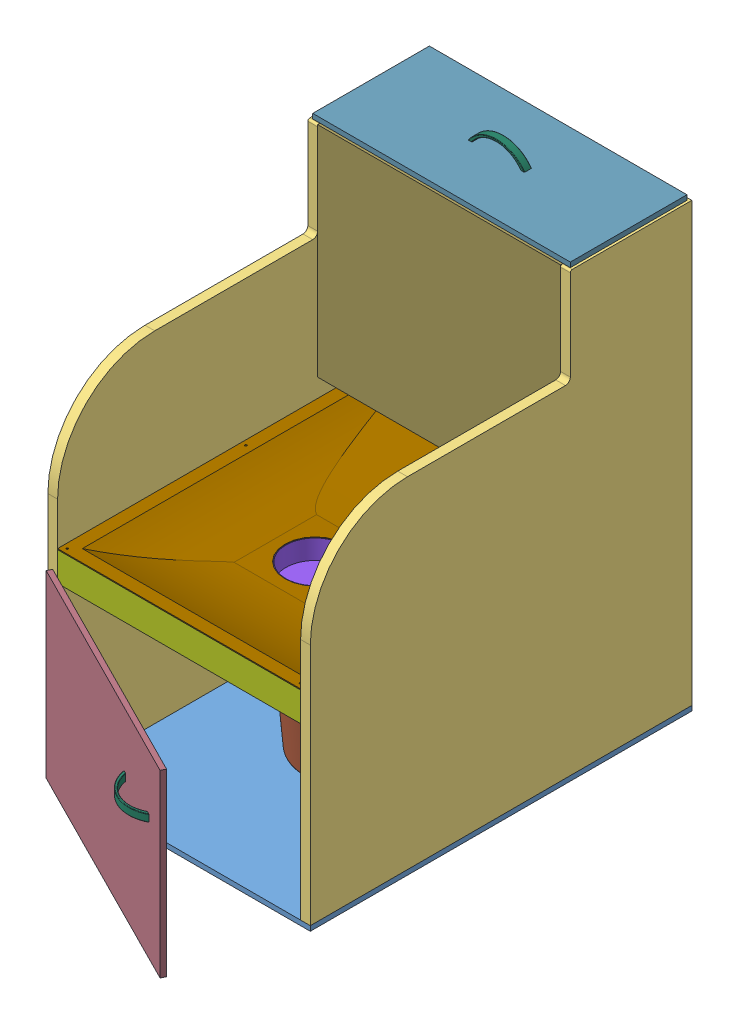
SolidWorks assembly toilet, configuration Varsayılan. Lengths in mm.
Overall size (540 949.81 1035.92).
19 component instances, 15 part files, 37 mates.
Components (placement in the parent):
- floor-1: floor [Default] at (270 0 490) size (540 10 785)
- back_wall-1: back_wall [Varsayılan] at (270 460 97.5) size (500 900 20)
- side_wall-1: side_wall [Varsayılan] at (0 310 382.5) x (0 0 -1) z (1 0 0) size (785 900 20)
- side_wall-2: side_wall [Varsayılan] at (520 310 382.5) x (0 0 -1) z (1 0 0) size (785 900 20)
- base_of_tank-1: base_of_tank [Varsayılan] at (270 495.1719 226.3244) x (-1 0 0) z (0 0.224951 -0.97437) size (500 10 228.2)
- inner1_of_tank-1: inner1_of_tank [Varsayılan] at (270 570.9137 252.0562) x (-1 0 0) z (0 -0.224951 -0.97437) size (500 10 180)
- side_row-1: side_row [Default] at (30 360 505) size (20 60 715)
- side_row-2: side_row [Default] at (510 360 505) size (20 60 715)
- back_row-1: back_row [Default] at (270 390 147.5) x (1 0 0) z (0 1 0) size (500 20 60)
- back_row-2: back_row [Default] at (270 390 882.5) x (1 0 0) z (0 1 0) size (500 20 60)
- plastic_D124mm-1: plastic_D124mm [Varsayılan] at (270 341.4 602.5) size (134 42 134)
- Evye_R2-1: Evye_R2 [Varsayılan] at (270 382 502.5) x (-1 0 0) z (0 0 -1) size (500 83.24 755)
- base_under_metal-1: base_under_metal [Varsayılan] at (270 360 522.5) size (500 10 400)
- plastic_waste_bin-1: plastic_waste_bin [Varsayılan] at (270 10 515) size (280 300 280)
- front_of_tank-2: front_of_tank [Varsayılan] at (270 685 337.5) size (500 450 10)
- front_door-1: front_door [Varsayılan] at (246.5671 195 1001.9194) x (0.892706 0 0.450639) z (-0.450639 0 0.892706) size (530 370 10)
- top_door-1: top_door [Varsayılan] at (270 910 222.5) x (1 0 0) z (0 1 0) size (530 240 10)
- handle-1: handle [Varsayılan] at (380.2911 266.9747 1080.6253) x (0.892706 0 0.450639) z (0 -1 0) size (116.18 29.81 15.2)
- handle-2: handle [Varsayılan] at (270 920 215) size (116.18 29.81 15.2)
Mates (geometry in assembly coordinates):
- Coincident89: coincident: point of floor-1; point of side_wall-1
- Coincident90: coincident: point of floor-1; point of side_wall-2
- Coincident98: coincident anti-aligned: line of side_wall-1 through (20 510 882.5) axis (0 -1 0); line of back_row-2 through (20 360 882.5) axis (0 1 0)
- Distance3: distance = 350 mm anti-aligned: plane of back_row-2 through (20 360 862.5) normal (0 -1 0); plane of floor-1 through (270 10 490) normal (0 1 0)
- Coincident102: coincident anti-aligned: line of side_row-1 through (20 420 862.5) axis (0 -1 0); line of back_row-2 through (20 360 862.5) axis (0 1 0)
- Coincident103: coincident aligned: plane of side_row-1 through (30 360 505) normal (0 -1 0); plane of back_row-2 through (20 360 862.5) normal (0 -1 0)
- Coincident104: coincident aligned: line of side_row-2 through (520 420 862.5) axis (0 -1 0); line of back_row-2 through (520 420 862.5) axis (0 -1 0)
- Coincident105: coincident aligned: plane of side_row-2 through (510 360 505) normal (0 -1 0); plane of back_row-2 through (20 360 862.5) normal (0 -1 0)
- Coincident106: coincident anti-aligned: line of side_row-1 through (20 420 147.5) axis (0 -1 0); line of back_row-1 through (20 360 147.5) axis (0 1 0)
- Coincident107: coincident aligned: plane of side_row-2 through (510 360 505) normal (0 -1 0); plane of back_row-1 through (20 360 127.5) normal (0 -1 0)
- Concentric1: concentric anti-aligned: circle of plastic_D124mm-1; circle of Evye_R2-1
- Coincident120: coincident aligned: circle of plastic_D124mm-1; plane of Evye_R2-1 through (270 382 502.5) normal (0 -1 0)
- Coincident122: coincident anti-aligned: plane of side_wall-2 through (520 510 682.5) normal (-1 0 0); plane of base_under_metal-1 through (520 350 322.5) normal (1 0 0)
- Coincident138: coincident anti-aligned: plane of floor-1 through (270 10 490) normal (0 1 0); circle of plastic_waste_bin-1
- Coincident155: coincident aligned: plane of side_wall-1 through (20 910 97.5) normal (0 1 0); plane of front_of_tank-2 through (20 910 347.5) normal (0 1 0)
- Coincident147: coincident anti-aligned: plane of floor-1 through (270 10 490) normal (0 1 0); plane of front_door-1 through (5.4936 10 891.4271) normal (0 -1 0)
- Coincident149: coincident: moEndPointRef_w of side_wall-1; line of front_door-1 through (10 380 882.5) axis (0 -1 0)
- Coincident151: coincident anti-aligned: plane of side_wall-2 through (540 910 97.5) normal (0 1 0); plane of top_door-1 through (270 910 222.5) normal (0 -1 0)
- Distance18: distance = 5 mm aligned: plane of side_wall-1 through (0 510 682.5) normal (-1 0 0); plane of top_door-1 through (5 920 342.5) normal (-1 0 0)
- Coincident156: coincident anti-aligned: plane of front_door-1 through (242.0607 195 1010.8465) normal (-0.450639 0 0.892706); plane of handle-1 through (335.6558 251.9747 1058.0933) normal (0.450639 0 -0.892706)
- Parallel3: parallel aligned: plane of front_door-1 through (5.4936 380 891.4271) normal (0 1 0); plane of handle-1 through (396.6929 266.9747 1048.1337) normal (0 1 0)
- Coincident163: coincident anti-aligned: plane of top_door-1 through (270 920 222.5) normal (0 1 0); plane of handle-2 through (320 920 230) normal (0 -1 0)
- Distance16: distance = 207 mm: line of handle-2 through (328 920 229) axis (0 0 -1); line of top_door-1 through (535 920 342.5) axis (0 0 -1)
- Distance17: distance = 112.5 mm: line of handle-2 through (321.2317 920 230) axis (1 0 0); line of top_door-1 through (5 920 342.5) axis (1 0 0)
- Coincident164: coincident anti-aligned: plane of side_wall-2 through (520 510 682.5) normal (-1 0 0); plane of Evye_R2-1 through (520 422 127.5) normal (1 0 0)
- Coincident165: coincident anti-aligned: plane of side_row-2 through (510 420 505) normal (0 1 0); plane of Evye_R2-1 through (495 420 882.5) normal (0 -1 0)
- Concentric2: concentric aligned: cylinder of plastic_D124mm-1 through (270 383.4 602.5) axis (0 -1 0) radius 62; circle of base_under_metal-1
- Coincident168: coincident anti-aligned: plane of floor-1 through (270 10 490) normal (0 1 0); plane of back_wall-1 through (20 10 117.5) normal (0 -1 0)
- Coincident169: coincident aligned: plane of back_row-2 through (270 390 882.5) normal (0 0 1); plane of Evye_R2-1 through (520 422 882.5) normal (0 0 1)
- Coincident171: coincident anti-aligned: plane of side_row-2 through (510 360 505) normal (0 -1 0); plane of base_under_metal-1 through (270 360 522.5) normal (0 1 0)
- Coincident173: coincident aligned: plane of back_wall-1 through (270 460 97.5) normal (0 0 -1); plane of side_wall-1 through (20 410 97.5) normal (0 0 -1)
- Coincident174: coincident aligned: plane of side_wall-1 through (20 910 347.5) normal (0 0 1); plane of front_of_tank-2 through (270 685 347.5) normal (0 0 1)
- Width1: width aligned: plane of front_of_tank-2 through (270 685 347.5) normal (0 0 1); plane of back_wall-1 through (270 460 97.5) normal (0 0 -1); plane of top_door-1 through (5 920 342.5) normal (0 0 1); plane of top_door-1 through (5 920 102.5) normal (0 0 -1)
- Coincident185: coincident anti-aligned: plane of side_wall-1 through (20 510 682.5) normal (1 0 0); plane of base_of_tank-1 through (20 530.5825 117.3983) normal (-1 0 0)
- Coincident186: coincident anti-aligned: plane of base_of_tank-1 through (520.001 469.505 337.5) normal (0 0 1); plane of front_of_tank-2 through (270 685 337.5) normal (0 0 -1)
- Coincident187: coincident anti-aligned: plane of inner1_of_tank-1 through (520 600.903 337.5) normal (0 0 1); plane of front_of_tank-2 through (270 685 337.5) normal (0 0 -1)
- Coincident188: coincident anti-aligned: plane of side_wall-1 through (20 510 682.5) normal (1 0 0); plane of inner1_of_tank-1 through (20 560.4118 162.1134) normal (-1 0 0)
